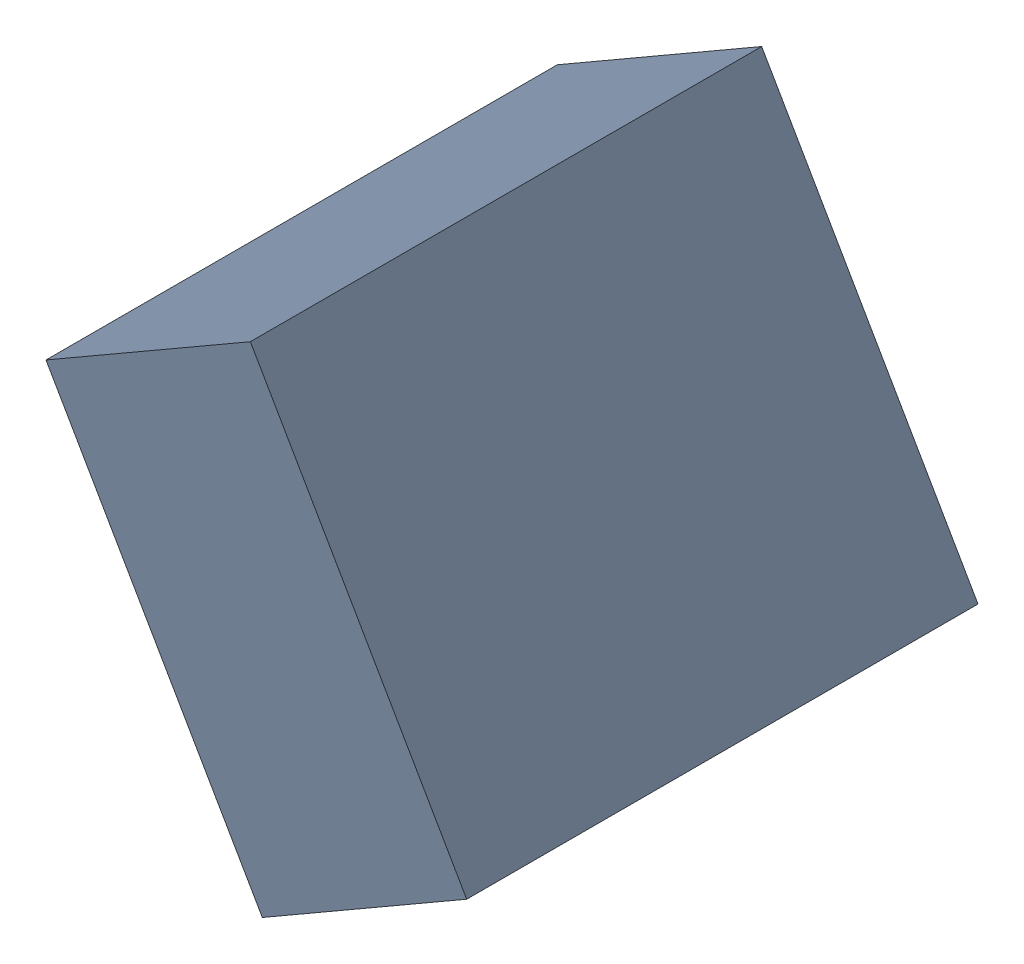
SolidWorks assembly C24_TDA5, configuration Standard. Lengths in mm.
Overall size (1.07 1.25 1.3).
2 component instances, 1 part files, 0 mates.
Components (placement in the parent):
- 885543192-1: 885543192 [Standard] at (-36.8924 -25.2763 0) size (1.07 1.25 1.3)
  - Extruded_27-1: Extruded_27 [Standard] at origin size (1.07 1.25 1.3)
